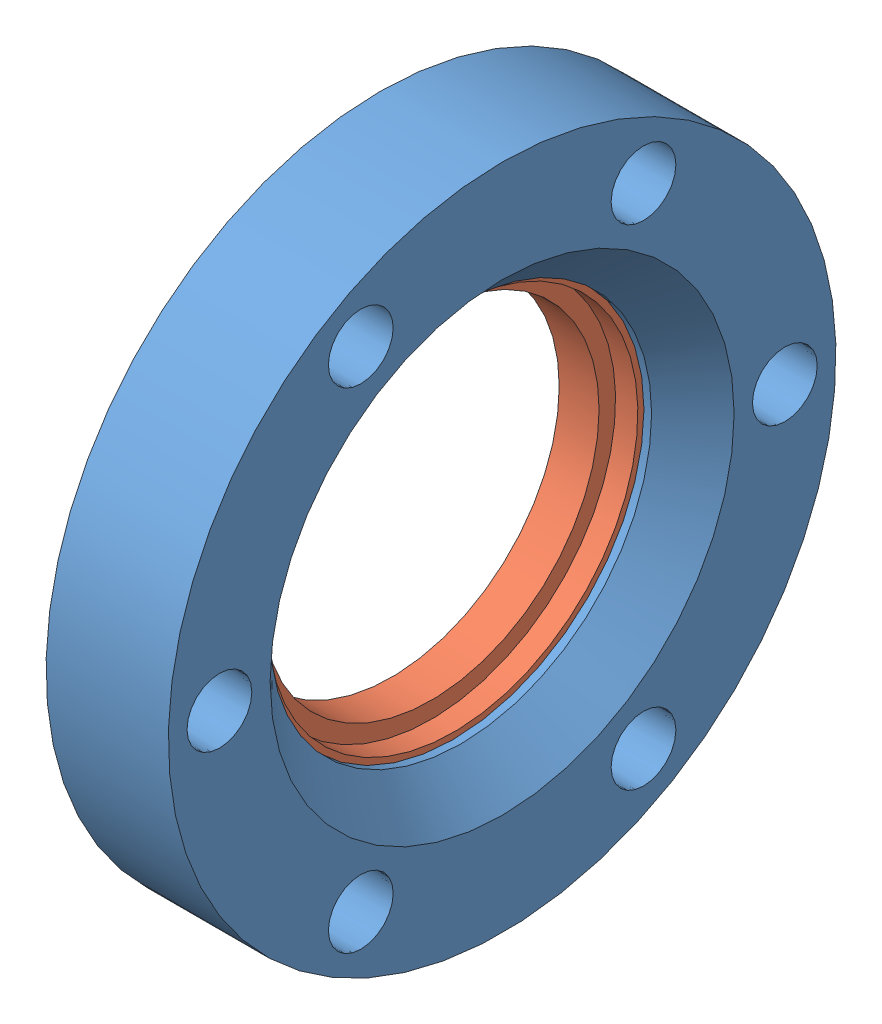
SolidWorks assembly 100014 (2.75 X 1.5 R), configuration Default. Lengths in mm.
Overall size (12.7 69.34 69.34).
2 component instances, 2 part files, 0 mates.
Components (placement in the parent):
- 100014 (2.75 X 1.5 REC)-1: 100014 (2.75 X 1.5 REC) [Default] at origin size (12.7 69.34 69.34)
- 100014 (2.75 X 1.5 INS)-1: 100014 (2.75 X 1.5 INS) [Default] at (1.17 0 0) x (1 0 0) z (0 0.994423 -0.105464) size (6.96 48.1 48.1)
